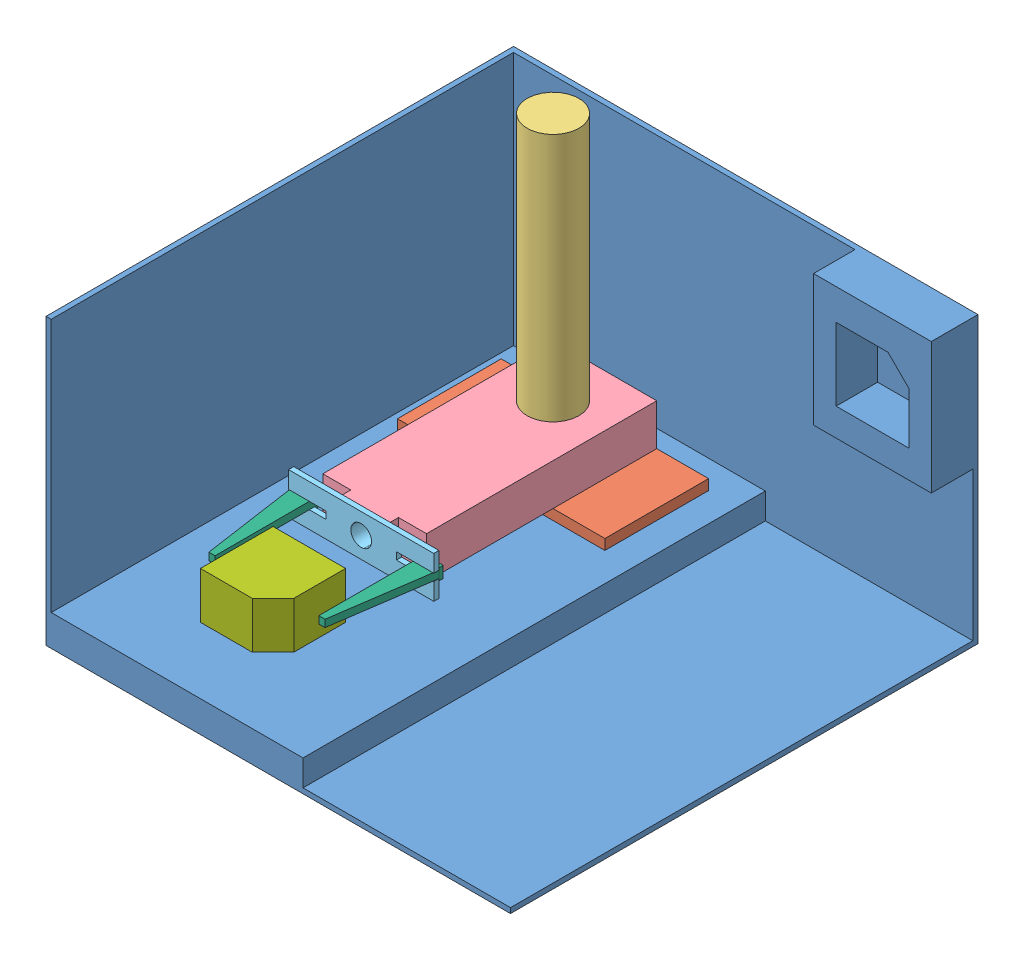
SolidWorks assembly Assem2, configuration Default. Lengths in mm.
Overall size (11375.6 8128 11450.1).
8 component instances, 7 part files, 18 mates.
Components (placement in the parent):
- CCBase-1: CCBase [Default] at origin size (11375.6 6981.21 11450.1)
- CCPlate_01-1: CCPlate_01 [Default] at (-2636.7765 889 -3641.7974) x (1 0 0) z (0 -1 0) size (5080 2540 254)
- CCPin-1: CCPin [Default] at (-2636.7765 4318 -3641.7974) x (1 0 0) z (0 -1 0) size (1270 1270 7620)
- CCPlate_02-1: CCPlate_02 [Default] at (-2636.7765 1524 -2092.3974) x (0 0 1) z (0 1 0) size (5842 2540 1016)
- CCGripper-1: CCGripper [Default] at (-2636.7765 1524 1057.2026) x (-1 0 0) z (0 -1 0) size (3556 3937 1016)
- Gripper_Arm-1: Gripper_Arm [Default] at (-4160.7765 1524 825.2422) x (0 -1 0) z (-1 0 0) size (279.4 2540 508)
- CCBlock-2: CCBlock [Default] at (-2636.7765 1016 3216.2026) x (1 0 0) z (0 1 0) size (1778 1778 1778)
- Gripper_Arm-3: Gripper_Arm [Default] at (-1112.7765 1524 825.2422) x (0 1 0) z (1 0 0) size (279.4 2540 508)
Mates (geometry in assembly coordinates):
- ProfileCenter1: profile center = 0 mm anti-aligned: circle of CCPlate_01-1; circle of CCBase-1
- ProfileCenter2: profile center = 0 mm anti-aligned: circle of CCPin-1; circle of CCBase-1
- Concentric1: concentric anti-aligned: cylinder of CCPin-1 through (-2636.7765 508 -3641.7974) axis (0 1 0) radius 635; cylinder of CCPlate_02-1 through (-2636.7765 2032 -3641.7974) axis (0 -1 0) radius 635
- Arm_Angle: planar angle = 0 rad aligned: plane of CCPlate_02-1 through (-2636.7765 1524 -2092.3974) normal (1 0 0); plane of CCPin-1 through (-2636.7765 4318 -3641.7974) normal (1 0 0)
- Arm_Hight: distance = 0 mm anti-aligned: plane of CCPlate_01-1 through (-2636.7765 1016 -3641.7974) normal (0 1 0); plane of CCPlate_02-1 through (-2636.7765 1016 -2092.3974) normal (0 -1 0)
- Concentric2: concentric aligned: cylinder of CCPlate_02-1 through (-2636.7765 1524 -1609.7974) axis (0 0 1) radius 381; cylinder of CCGripper-1 through (-2636.7765 1524 1057.2026) axis (0 0 1) radius 381
- Grip_Angle: planar angle = 0 rad anti-aligned: plane of CCPlate_02-1 through (-2636.7765 1524 -2092.3974) normal (0 1 0); plane of CCGripper-1 through (-2636.7765 1524 1057.2026) normal (0 -1 0)
- Coincident6: coincident aligned: plane of CCGripper-1 through (-2636.7765 1524 2835.2026) normal (0 -1 0); plane of ? through (-2636.7765 1524 3216.2026) normal (0 -1 0)
- Dist_To_Block: distance = 1270 mm anti-aligned: plane of CCGripper-1 through (-2636.7765 1524 1057.2026) normal (0 0 1); plane of ?
- Distance4: distance = 1600.2 mm anti-aligned: plane of CCPlate_02-1 through (-1366.7765 2032 727.0026) normal (0 0 1); plane of ? through (-3525.7765 635 2327.2026) normal (0 0 -1)
- Distance5: distance = 0 mm aligned: plane of ? through (-2636.7765 1524 3216.2026) normal (-1 0 0); plane of CCGripper-1 through (-2636.7765 1524 1057.2026) normal (-1 0 0)
- Coincident20: coincident anti-aligned: plane of CCGripper-1 through (-2636.7765 1524 930.2026) normal (0 0 -1); plane of Gripper_Arm-1 through (-4414.7765 1435.1 930.2026) normal (0 0 1)
- distance_to_block: distance = 381 mm anti-aligned: plane of Gripper_Arm-1 through (-3906.7765 1524 825.2422) normal (1 0 0); plane of CCBlock-2 through (-3525.7765 1905 2327.2026) normal (-1 0 0)
- Coincident33: coincident anti-aligned: plane of CCGripper-1 through (-2636.7765 1524 1057.2026) normal (-1 0 0); plane of CCBlock-2 through (-2636.7765 1016 3216.2026) normal (1 0 0)
- distanct_to_block: distance = 1270 mm anti-aligned: plane of CCGripper-1 through (-2636.7765 1524 1057.2026) normal (0 0 1); plane of CCBlock-2 through (-1747.7765 1905 2327.2026) normal (0 0 -1)
- Coincident35: coincident anti-aligned: plane of CCGripper-1 through (-2636.7765 1612.9 930.2026) normal (0 -1 0); plane of Gripper_Arm-1 through (-4414.7765 1612.9 3365.2422) normal (0 1 0)
- Distance15: distance = 508 mm anti-aligned: plane of CCGripper-1 through (-2636.7765 1524 1057.2026) normal (0 -1 0); plane of CCBlock-2 through (-2636.7765 1016 3216.2026) normal (0 1 0)
- Distance16: distance = 1600.2 mm anti-aligned: plane of CCPlate_02-1 through (-1366.7765 2032 727.0026) normal (0 0 1); plane of CCBlock-2 through (-1747.7765 1905 2327.2026) normal (0 0 -1)
